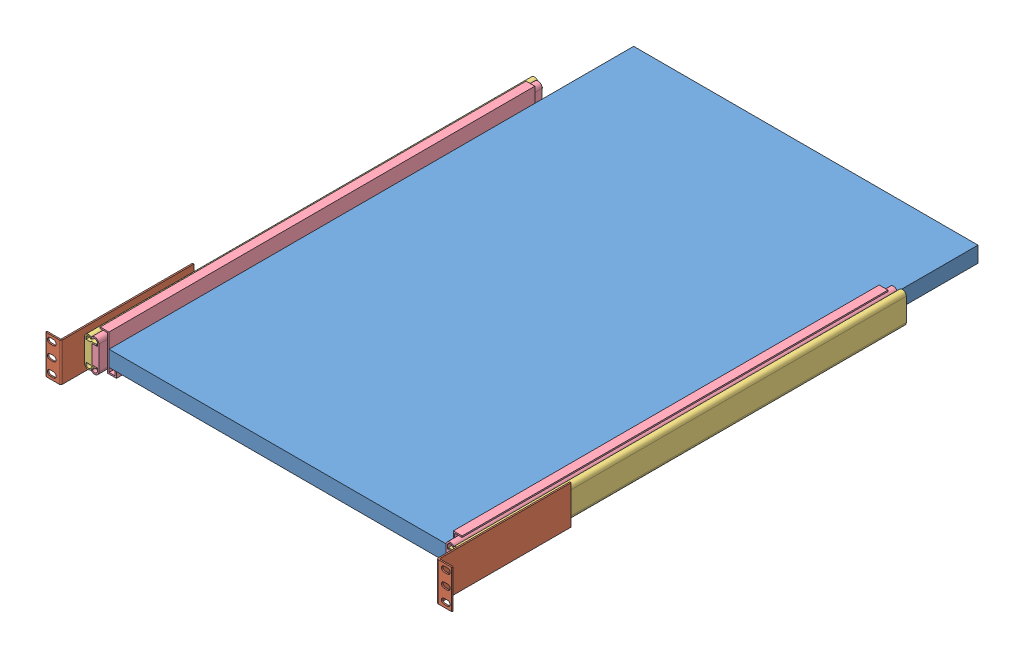
SolidWorks assembly Router-Schublade, configuration Standard. Lengths in mm.
Overall size (464.8 44.9 737).
9 component instances, 4 part files, 6 mates.
Components (placement in the parent):
- Platte-1: Platte [Standard] at (-201.5811 50.5043 900) size (393.8 18 700)
- Gleitschiene-Left-1: Gleitschiene-Left [Standard] at (-230.5216 -87.7457 884.2457) x (0 0 1) z (0 1 0) size (537 44.1 44)
  - winkel-1: winkel [Standard] at (51.9543 -6.5595 130.1) size (152.1 17.5 44)
  - Schine-1: Schine [Standard] at (-484.2457 10.9405 134.15) x (0 1 0) z (1 0 0) size (13.6 35 510)
  - Rolle-1: Rolle [Standard] at (-471.2457 35.9405 133.25) x (0 1 0) z (1 0 0) size (19.2 41.6 507)
- Gleitschiene-Right-1: Gleitschiene-Right [Standard] at (221.1594 215.5543 884.2457) x (0 0 1) z (0 -1 0) size (537 44.1 44.05)
  - winkel-1: winkel [Standard] at (51.9543 -6.5595 130.1) size (152.1 17.5 44)
  - Schine-1: Schine [Standard] at (-484.2457 10.9405 134.15) x (0 1 0) z (1 0 0) size (13.6 35 510)
  - Rolle-1: Rolle [Standard] at (15.7543 35.9405 170.05) x (0 1 0) z (-1 0 0) size (19.2 41.6 507)
Mates (geometry in assembly coordinates):
- Deckungsgleich1: coincident anti-aligned: plane of Platte-1 through (-201.5811 68.5043 900) normal (-1 0 0); plane of Gleitschiene-Left-1/Rolle-1 through (-201.5811 45.5043 900) normal (1 0 0)
- Deckungsgleich2: coincident anti-aligned: plane of Platte-1 through (-201.5811 50.5043 900) normal (0 -1 0); plane of Gleitschiene-Left-1/Rolle-1 through (-192.9811 50.5043 900) normal (0 1 0)
- Deckungsgleich3: coincident aligned: plane of Platte-1 through (-201.5811 68.5043 900) normal (0 0 1); plane of Gleitschiene-Left-1/Rolle-1 through (-194.5811 45.5043 900) normal (0 0 1)
- Deckungsgleich4: coincident anti-aligned: plane of Platte-1 through (192.2189 68.5043 900) normal (1 0 0); plane of Gleitschiene-Right-1/Rolle-1 through (192.2189 45.5043 413) normal (-1 0 0)
- Deckungsgleich5: coincident anti-aligned: plane of Platte-1 through (-201.5811 50.5043 900) normal (0 -1 0); plane of Gleitschiene-Right-1/Rolle-1 through (183.6189 50.5043 413) normal (0 1 0)
- Deckungsgleich6: coincident aligned: plane of Platte-1 through (-201.5811 68.5043 900) normal (0 0 1); plane of Gleitschiene-Right-1/Rolle-1 through (185.2189 45.5043 900) normal (0 0 1)
